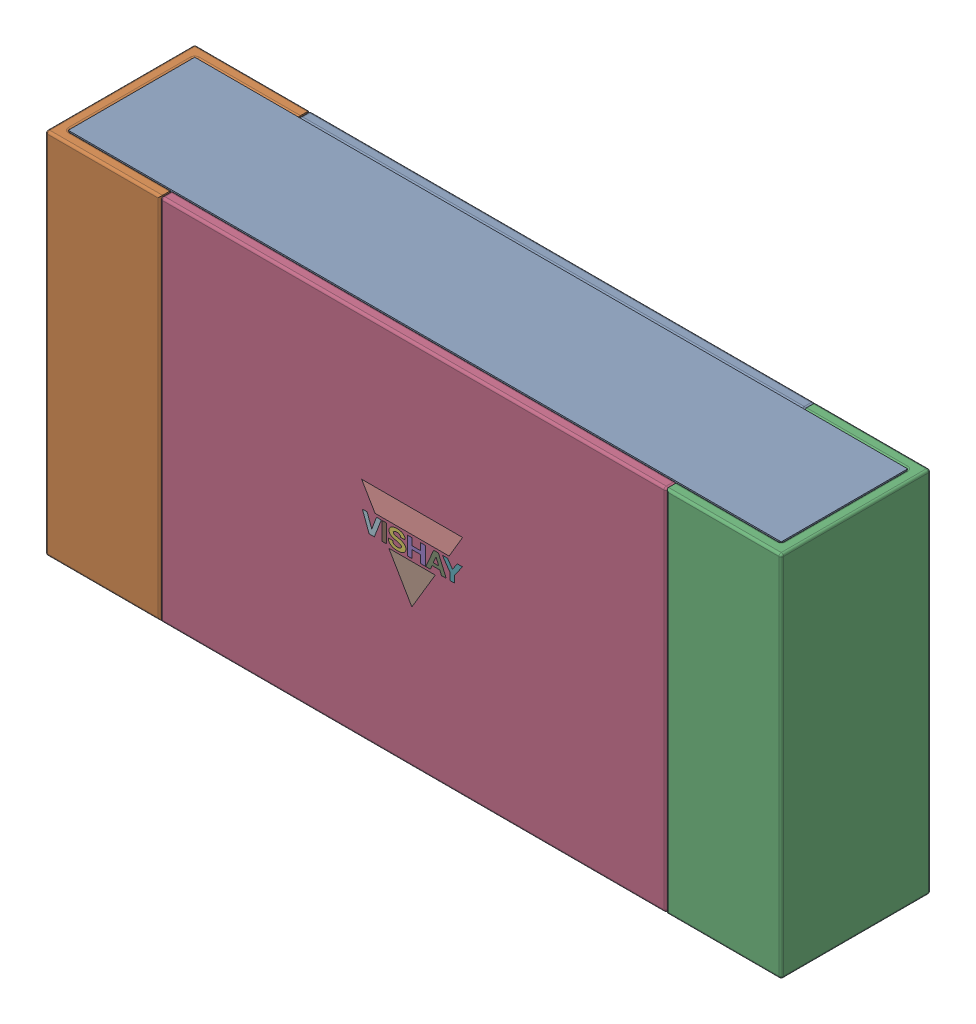
SolidWorks assembly 6, configuration Défaut. Lengths in mm.
Overall size (3.2 1.6 0.65).
7 component instances, 5 part files, 0 mates.
Components (placement in the parent):
- Res_Vishay_MCA12060D1541BP100_eec-1: Res_Vishay_MCA12060D1541BP100_eec [Défaut] at (-16.5038 29.591 0) x (1 0 0) z (0 0 1) size (3.2 1.6 0.65)
  - body-1: body [Défaut] at (0 0 0.6) x (1 0 0) z (0 0 -1) size (3.1 1.6 0.55)
  - pad-1: pad [Défaut] at (-1.4133 -0.8 0.65) x (1 0 0) z (0 1 0) size (0.5 0.65 1.6)
  - pad-2: pad [Défaut] at (1.4133 0.8 0.65) x (-1 0 0) z (0 -1 0) size (0.5 0.65 1.6)
  - top-1: top [Défaut] at (0 0 0.65) x (1 0 0) z (0 0 -1) size (2.2 1.6 0.05)
  - Vishay-1: Vishay [Défaut] at (0.0405 -0.7888 0.65) size (0.45 0.38 0.01)
  - bottom-1: bottom [Défaut] at (0 0 0.05) x (1 0 0) z (0 0 -1) size (2.2 1.6 0.05)
